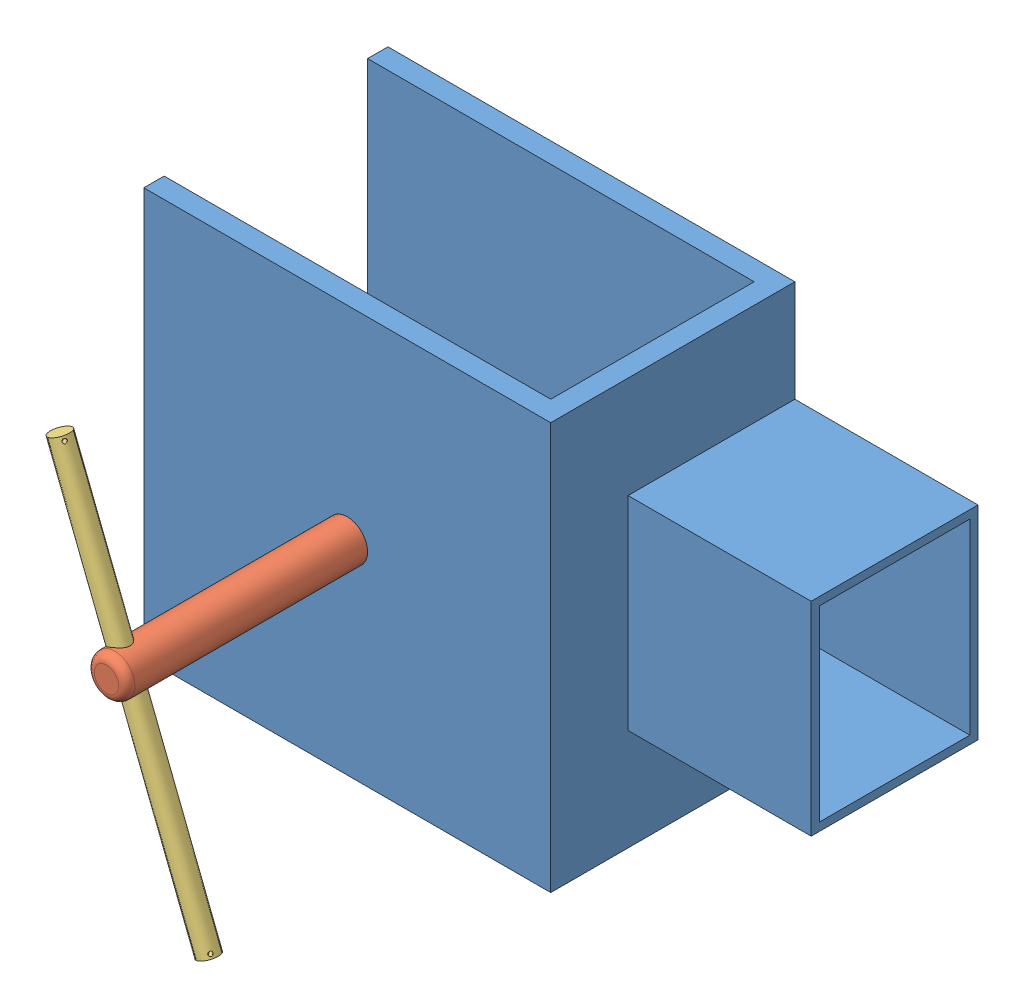
SolidWorks assembly bloccaggio, configuration Default. Lengths in mm.
Overall size (145 102.43 119.16).
3 component instances, 3 part files, 3 mates.
Components (placement in the parent):
- bloccaggio 1-1: bloccaggio 1 [Default] at (10.9076 54.1426 208.057) x (0 0 1) z (-1 0 0) size (60 100 145)
- bloccaggio 2-1: bloccaggio 2 [Default] at (-39.0924 54.1426 227.2183) x (-0.930705 -0.365771 0) z (-0.365771 0.930705 0) size (20 71 20)
- bloccaggio 3-1: bloccaggio 3 [Default] at (-18.975 2.9538 292.2183) x (0.456617 0.179452 -0.871377) z (-0.365771 0.930705 0) size (5 5 100)
Mates (geometry in assembly coordinates):
- Vite2: screw = 10 mm anti-aligned: cylinder of bloccaggio 1-1 through (-39.0924 54.1426 217.057) axis (0 0 1) radius 5; cylinder of bloccaggio 2-1 through (-39.0924 54.1426 297.2183) axis (0 0 -1) radius 5
- Concentrico14: concentric anti-aligned: cylinder of bloccaggio 2-1 through (-37.2635 49.489 292.2183) axis (-0.365771 0.930705 0) radius 2.5; cylinder of bloccaggio 3-1 through (-55.552 96.0243 292.2183) axis (0.365771 -0.930705 0) radius 2.5
- Distanza7: distance = 50 mm aligned: plane of bloccaggio 3-1 through (-18.975 2.9538 292.2183) normal (0.365771 -0.930705 0); cylinder of bloccaggio 2-1 through (-39.0924 54.1426 297.2183) axis (0 0 -1) radius 5
